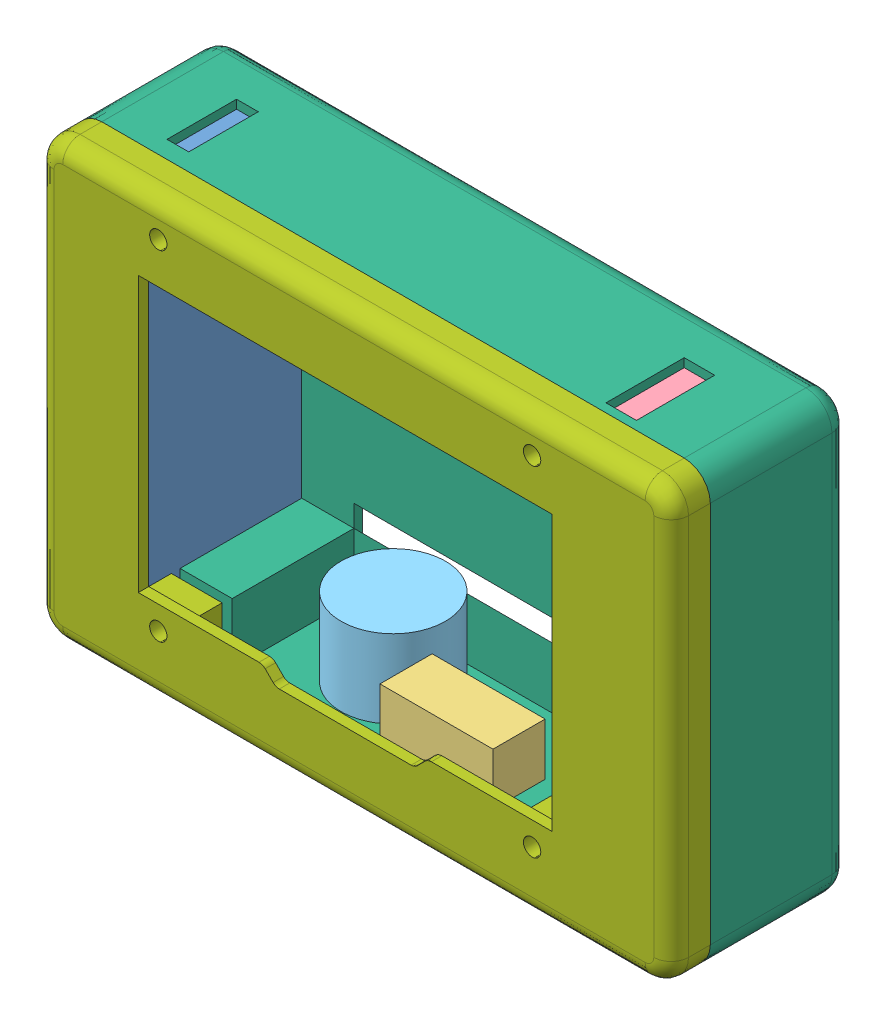
SolidWorks assembly Assem1, configuration Default. Lengths in mm.
Overall size (73 53 21.58).
9 component instances, 9 part files, 22 mates.
Components (placement in the parent):
- display-1: display [Default] at (-1.7258 10.2348 25.1975) size (47 43 7.5) (hidden)
- ardu+pressure-1: ardu+pressure [Default] at (-11.7258 9.7348 13.1975) x (0 1 0) z (1 0 0) size (44.5 18 9)
- battery-1: battery [Default] at (46.2742 48.2348 17.1975) x (-1 0 0) z (0 0 1) size (49 30 8) (hidden)
- povish-1: povish [Default] at (57.2742 15.7348 31.1975) x (0 1 0) z (-1 0 0) size (37.5 17 7)
- vikl-1: vikl [Default] at (20.2742 14.2348 21.1975) x (1 0 0) z (0 -1 0) size (13 6 12)
- заряд-1: заряд [Default] at (46.2742 25.2348 31.1975) x (0 0 -1) z (1 0 0) size (17 29 4)
- buzzer-1: buzzer [Default] at (13.7977 7.2312 19.1975) x (0.88949 0 -0.456954) z (0 1 0) size (12 12 9)
- korp-niz-1: korp-niz [Default] at (22.7742 30.2348 12.1975) size (73 50 16)
- korp-verh-1: korp-verh [Default] at (59.2742 5.2348 32.6975) x (-1 0 0) z (0 0 -1) size (73 50 4.5)
Mates (geometry in assembly coordinates):
- Coincident1: coincident anti-aligned: plane of display-1 through (-1.7258 10.2348 25.1975) normal (0 0 -1); plane of battery-1 through (46.2742 48.2348 25.1975) normal (0 0 1)
- Distance1: distance = 5 mm aligned: plane of battery-1 through (46.2742 48.2348 25.1975) normal (0 1 0); plane of display-1 through (-1.7258 53.2348 28.1975) normal (0 1 0)
- Distance2: distance = 1 mm aligned: plane of battery-1 through (46.2742 48.2348 25.1975) normal (1 0 0); plane of display-1 through (45.2742 10.2348 28.1975) normal (1 0 0)
- Coincident3: coincident anti-aligned: plane of povish-1 through (50.2742 15.7348 31.1975) normal (-1 0 0); plane of заряд-1 through (50.2742 25.2348 31.1975) normal (1 0 0)
- Coincident4: coincident aligned: plane of povish-1 through (50.2742 15.7348 14.1975) normal (0 0 -1); plane of заряд-1 through (50.2742 25.2348 14.1975) normal (0 0 -1)
- Coincident5: coincident aligned: plane of povish-1 through (50.2742 53.2348 31.1975) normal (0 1 0); plane of заряд-1 through (50.2742 53.2348 31.1975) normal (0 1 0)
- Coincident7: coincident aligned: plane of display-1 through (-1.7258 53.2348 28.1975) normal (0 1 0); plane of povish-1 through (50.2742 53.2348 31.1975) normal (0 1 0)
- Distance5: distance = 2 mm aligned: plane of vikl-1 through (20.2742 8.2348 21.1975) normal (0 -1 0); plane of display-1 through (-1.7258 10.2348 28.1975) normal (0 -1 0)
- Distance6: distance = 12 mm aligned: plane of vikl-1 through (33.2742 8.2348 21.1975) normal (1 0 0); plane of display-1 through (45.2742 10.2348 28.1975) normal (1 0 0)
- Tangent1: tangent anti-aligned: plane of display-1 through (-1.7258 10.2348 25.1975) normal (0 0 -1); cylinder of buzzer-1 through (13.7977 16.2312 19.1975) axis (0 -1 0) radius 6
- Coincident9: coincident anti-aligned: plane of battery-1 through (46.2742 48.2348 25.1975) normal (1 0 0); plane of заряд-1 through (46.2742 25.2348 31.1975) normal (-1 0 0)
- Distance7: distance = 1.5 mm aligned: plane of заряд-1 through (50.2742 25.2348 31.1975) normal (0 0 1); plane of display-1 through (-1.7258 10.2348 32.6975) normal (0 0 1)
- Coincident10: coincident anti-aligned: plane of ardu+pressure-1 through (-2.7258 9.7348 13.1975) normal (1 0 0); plane of battery-1 through (-2.7258 48.2348 25.1975) normal (-1 0 0)
- Distance8: distance = 1.5 mm aligned: plane of ardu+pressure-1 through (-2.7258 9.7348 31.1975) normal (0 0 1); plane of display-1 through (-1.7258 10.2348 32.6975) normal (0 0 1)
- Coincident11: coincident aligned: plane of display-1 through (-1.7258 53.2348 28.1975) normal (0 1 0); plane of ardu+pressure-1 through (-2.7258 53.2348 13.1975) normal (0 1 0)
- Coincident12: coincident anti-aligned: plane of ardu+pressure-1 through (-2.7258 9.7348 13.1975) normal (0 0 -1); plane of korp-niz-1 through (22.7742 30.2348 13.1975) normal (0 0 1)
- Coincident13: coincident anti-aligned: plane of ardu+pressure-1 through (-2.7258 53.2348 13.1975) normal (0 1 0); plane of korp-niz-1 through (-11.7258 53.2348 28.1975) normal (0 -1 0)
- Coincident14: coincident anti-aligned: plane of povish-1 through (57.2742 15.7348 31.1975) normal (1 0 0); plane of korp-niz-1 through (57.2742 7.2348 28.1975) normal (-1 0 0)
- Distance9: distance = 1 mm aligned: plane of vikl-1 through (20.2742 8.2348 27.1975) normal (0 0 1); plane of display-1 through (-1.7258 10.2348 28.1975) normal (0 0 1)
- Coincident15: coincident anti-aligned: plane of korp-niz-1 through (22.7742 30.2348 28.1975) normal (0 0 1); plane of korp-verh-1 through (59.2742 5.2348 28.1975) normal (0 0 -1)
- Coincident16: coincident aligned: plane of korp-niz-1 through (-13.7258 5.2348 13.1975) normal (-1 0 0); plane of korp-verh-1 through (-13.7258 5.2348 31.4975) normal (-1 0 0)
- Coincident17: coincident aligned: plane of korp-niz-1 through (-13.7258 55.2348 13.1975) normal (0 1 0); plane of korp-verh-1 through (59.2742 55.2348 31.4975) normal (0 1 0)
